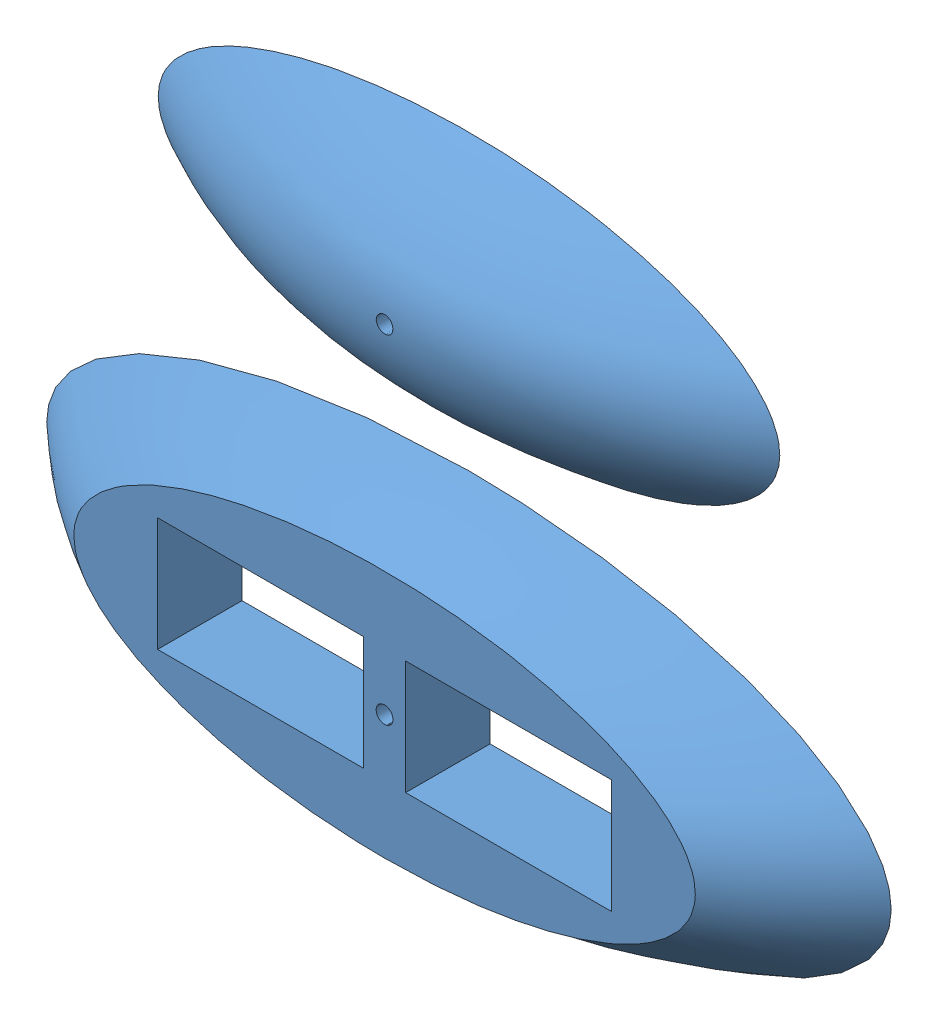
SolidWorks assembly Assem1, configuration Default. Lengths in mm.
Overall size (508 387.8 51.05).
2 component instances, 1 part files, 6 mates.
Components (placement in the parent):
- EllipsoidHull-1: EllipsoidHull [Layer 3] at (0 0 -50.8) x (-1 0 0) z (0 0 -1) size (391.1 166.39 51.05)
- EllipsoidHull-2: EllipsoidHull [Layer 2] at (0 -203.2 0) x (-1 0 0) z (0 0 -1) size (508 203.2 50.8)
Mates (geometry in assembly coordinates):
- Coincident1: coincident anti-aligned: plane of ? through (0 -177.8 0) normal (0 0 -1)
- Coincident2: coincident anti-aligned: plane of EllipsoidHull-1 through (0 0 0) normal (0 0 -1); plane of assembly
- Coincident3: coincident aligned: plane of EllipsoidHull-1; plane of assembly
- Distance1: distance = 203.2 mm aligned: plane of assembly; plane of EllipsoidHull-2
- Coincident5: coincident anti-aligned: plane of EllipsoidHull-1 through (0 0 -50.8) normal (-1 0 0); plane of assembly
- Coincident6: coincident anti-aligned: plane of ? through (0 -177.8 0) normal (-1 0 0)
